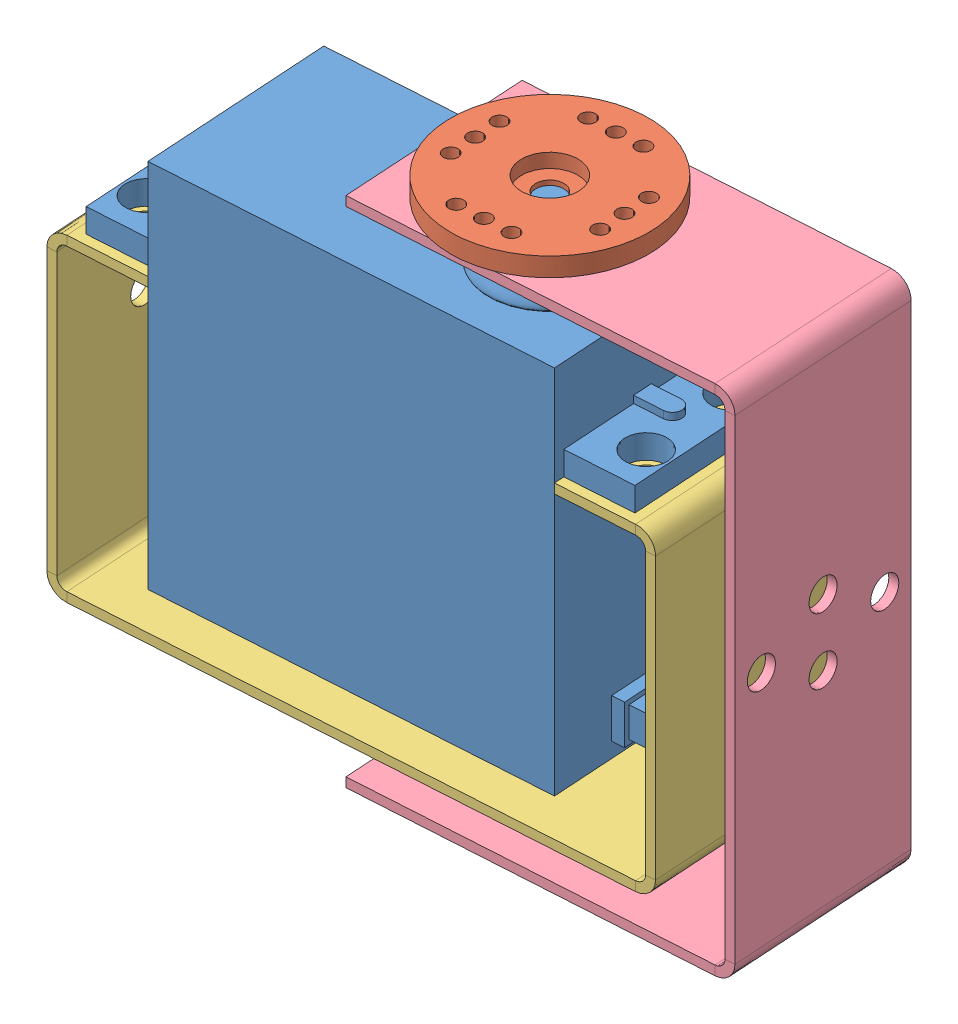
SolidWorks assembly servo_motor_bracket4, configuration ﾃﾞﾌｫﾙﾄ. Lengths in mm.
Overall size (70.06 56.5 24.3).
5 component instances, 5 part files, 8 mates.
Components (placement in the parent):
- servo_motor-1: servo_motor [ﾃﾞﾌｫﾙﾄ] at (-17.4766 -22.7875 66.9184) x (0.997976 0 -0.063591) z (0.063591 0 0.997976) size (54.94 45.5 20)
- servo_motor_soucer-1: servo_motor_soucer [ﾃﾞﾌｫﾙﾄ] at (13.2538 22.7125 54.94) x (0.99807 0 -0.062092) z (0.062092 0 0.99807) size (21.05 5.7 21.05)
- servo_bracket4_base-2: servo_bracket4_base [ﾃﾞﾌｫﾙﾄ] at (-27.5762 -27.7875 67.562) x (0.997976 0 -0.063591) z (0.063591 0 0.997976) size (60.94 33.81 20)
- servo_bracket4_cover-1: servo_bracket4_cover [ﾃﾞﾌｫﾙﾄ] at (40.2138 -31.7875 63.2821) x (0.99807 0 -0.062092) z (0.062092 0 0.99807) size (39 54.5 20)
- M3_spacer-1: M3_spacer [ﾃﾞﾌｫﾙﾄ] at (13.2538 -30.7875 54.94) size (7 3 7)
Mates (geometry in assembly coordinates):
- 一致3: coincident anti-aligned: circle of servo_motor-1; circle of servo_motor_soucer-1
- 同心円3: concentric aligned: circle of servo_motor-1; circle of servo_bracket4_base-2
- 一致4: coincident anti-aligned: plane of servo_motor-1 through (30.1792 6.0225 62.8197) normal (0 -1 0); plane of servo_bracket4_base-2 through (-27.5762 6.0225 67.562) normal (0 1 0)
- 同心円4: concentric aligned: circle of servo_motor_soucer-1; circle of servo_bracket4_cover-1
- 同心円5: concentric aligned: circle of servo_motor_soucer-1; circle of servo_bracket4_cover-1
- 一致6: coincident anti-aligned: plane of servo_motor_soucer-1 through (13.2538 22.7125 54.94) normal (0 -1 0); plane of servo_bracket4_cover-1 through (41.2119 22.7125 63.22) normal (0 1 0)
- 一致7: coincident anti-aligned: circle of servo_bracket4_base-2; circle of M3_spacer-1
- 同心円6: concentric aligned: circle of servo_motor-1; circle of servo_bracket4_base-2
